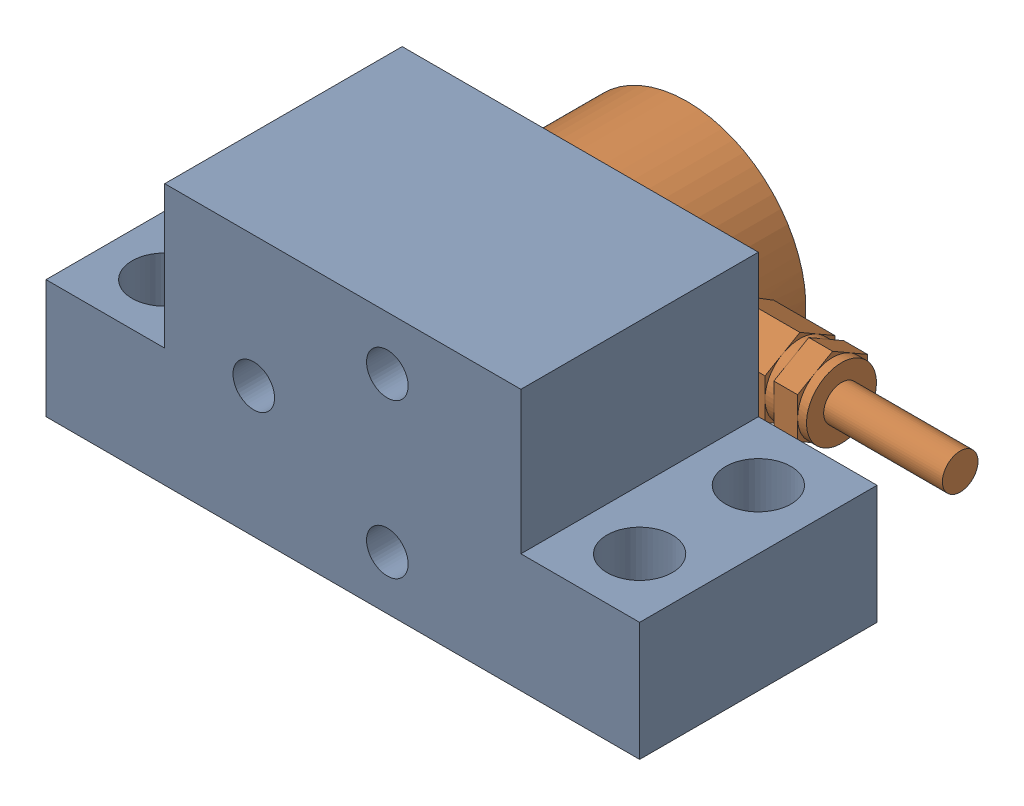
SolidWorks assembly Aynalamaloadcel yatay montaj-1, configuration Default. Lengths in mm.
Overall size (53.5 22 31).
2 component instances, 2 part files, 0 mates.
Components (placement in the parent):
- AynalamaLoadcell yatay ayak-1: AynalamaLoadcell yatay ayak [Default] at origin size (50 22 20)
- AynalamaMini_Loadcell-1: AynalamaMini_Loadcell [Default] at (0 11 -19) x (-1 0 0) z (0 -1 0) size (38.5 12 20)
